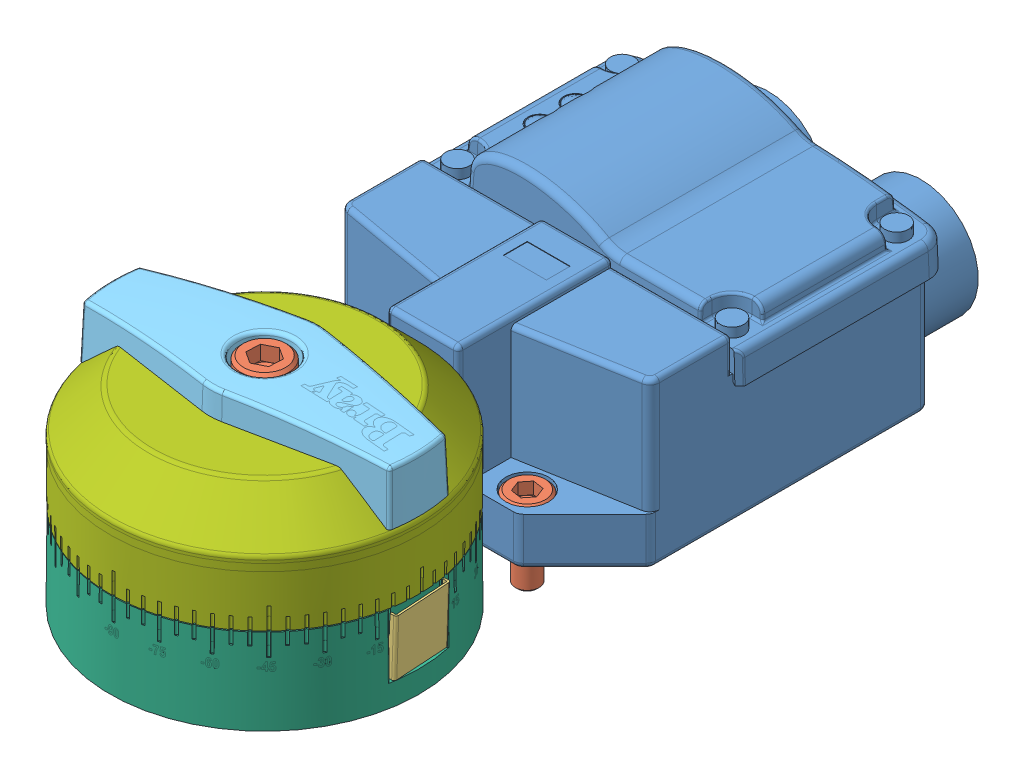
SolidWorks assembly Assem4, configuration Default. Lengths in mm.
Overall size (68 54.14 154.53).
10 component instances, 7 part files, 12 mates.
Components (placement in the parent):
- 54-0013-71104-1: 54-0013-71104 [Default] at (-78.2286 107.4034 21.6779) size (68 40.45 88.5)
- socket head cap screw_am-1: socket head cap screw_am [B18.3.1M - 5 x 0.8 x 12 Hex SHCS -- 12NHX] at (-93.2514 117.4034 48.1779) x (0 -1 0) z (-0.778168 0 0.628056) size (17 8.5 8.5)
- socket head cap screw_am-2: socket head cap screw_am [B18.3.1M - 6 x 1.0 x 30 Hex SHCS -- 30NHX] at (-78.24 154.2212 88.1829) x (0 -1 0) z (-0.546944 0 0.837169) size (36 10 10)
- 54-000A-73500-1: 54-000A-73500 [Default] at (-78.7714 132.9812 55.5261) x (-0.999979 0 0.00653) z (-0.00653 0 -0.999979) size (12.19 11.94 6.35)
- 54-048A-705P0-1: 54-048A-705P0 [Default] at (-78.24 136.3594 88.1829) size (44.92 12.57 44.92)
- 54-000A-92512-1: 54-000A-92512 [Default] at (-78.24 142.8872 88.1829) x (-0.999645 0 0.026634) z (-0.026634 0 -0.999645) size (64.52 13.44 23.07)
- 54-000A-92510-1: 54-000A-92510 [Default] at (-78.24 108.9274 88.1829) x (-0.018943 0 -0.999821) z (0.999821 0 -0.018943) size (64.81 35.64 64.77)
- 54-000A-92511-1: 54-000A-92511 [Default] at (-78.24 127.0122 88.1829) x (-0.999796 0 0.020182) z (-0.020182 0 -0.999796) size (64.76 21.97 66.01)
- socket head cap screw_am-3: socket head cap screw_am [B18.3.1M - 5 x 0.8 x 12 Hex SHCS -- 12NHX] at (-63.2286 117.4034 48.1779) x (0 -1 0) z (-0.778168 0 -0.628056) size (17 8.5 8.5)
- 54-000A-73500-2: 54-000A-73500 [Default] at (-45.7906 120.0562 87.526) x (-0.060648 0.001457 -0.998158) z (0.997549 -0.034869 -0.060662) size (12.19 11.94 6.35)
Mates (geometry in assembly coordinates):
- Concentric1: concentric: cylinder of socket head cap screw_am-2 through (-78.24 185.9712 88.1829) axis (0 1 0) radius 3; cylinder of 54-000A-92512-1 through (-78.24 142.8872 88.1829) axis (0 -1 0) radius 3.3
- Distance1: distance = 0.1778 mm: plane of 54-000A-92511-1 through (-78.0375 142.7094 98.2139) normal (0 1 0); plane of 54-000A-92512-1 through (-78.0428 142.8872 95.5844) normal (0 -1 0)
- Concentric2: concentric: cylinder of 54-000A-92512-1 through (-78.24 142.8872 88.1829) axis (0 -1 0) radius 3.3; cylinder of 54-000A-92511-1 through (-78.24 130.2006 88.1829) axis (0 1 0) radius 3.3
- Concentric3: concentric: cylinder of 54-000A-92512-1 through (-78.24 142.8872 88.1829) axis (0 -1 0) radius 3.3; cylinder of 54-000A-92510-1 through (-78.24 99.5936 88.1829) axis (0 1 0) radius 3.3
- Concentric4: concentric: cylinder of 54-0013-71104-1 through (-63.2286 102.5831 48.1779) axis (0 1 0) radius 4.5; cylinder of socket head cap screw_am-3 through (-63.2286 149.1534 48.1779) axis (0 1 0) radius 4.25
- Parallel1: parallel: plane of 54-000A-92510-1 through (-47.8162 113.5756 87.6065) normal (0.034893 0.999391 -0.000661); plane of 54-000A-73500-2 through (-45.6292 114.082 93.6147) normal (-0.034893 -0.999391 0.000661)
- Tangent1: tangent: line of 54-000A-73500-1 through (-72.6721 127.0122 56.0197) axis (0 1 0); face of 54-000A-92511-1
- Coincident1: coincident: plane of 54-000A-92510-1 through (-78.483 139.5344 75.3582) normal (0 1 0); plane of 54-000A-92511-1 through (-77.986 139.5344 100.7661) normal (0 -1 0)
- Coincident2: coincident: plane of 54-048A-705P0-1 through (-78.24 136.3594 88.1829) normal (0 1 0); plane of 54-000A-92510-1 through (-78.6466 136.3594 66.7238) normal (0 -1 0)
- Coincident3: coincident: plane of 54-000A-73500-1 through (-72.6755 127.0122 55.4863) normal (0 -1 0); plane of 54-000A-92511-1 through (-77.64 127.0122 117.9043) normal (0 -1 0)
- Coincident4: coincident: plane of socket head cap screw_am-2 through (-74.0541 148.2212 90.9177) normal (0 -1 0); circle of 54-000A-92512-1
- Coincident5: coincident: plane of 54-0013-71104-1 through (-63.2286 112.4034 48.1779) normal (0 1 0); plane of socket head cap screw_am-3 through (-65.8978 112.4034 51.4852) normal (0 -1 0)
